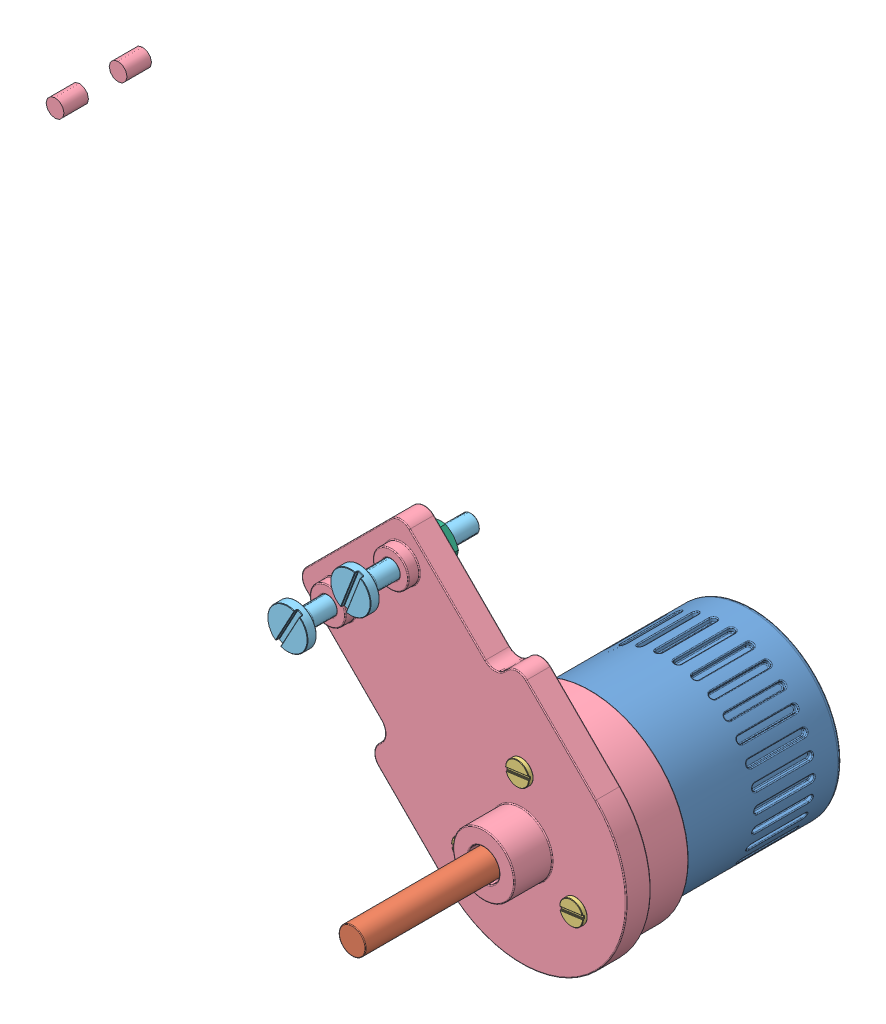
SolidWorks assembly Motor Assembly - other one, configuration Default. Lengths in mm.
Overall size (36.41 36.41 45.5).
13 component instances, 7 part files, 7 mates.
Components (placement in the parent):
- Motor-1: Motor [Default] at (-25.3397 14.6852 35.1852) size (20 20 26)
- Motor Shaft-1: Motor Shaft [Default] at (-25.3397 14.6852 55.1852) x (0.582298 0.812976 0) z (0 0 1) size (3 3 25)
- 1.25mm screw-1: 1.25mm screw [Default] at (-25.3397 21.6852 36.1852) x (0.133353 -0.991069 0) z (0 0 -1) size (2.65 2.65 7.5)
- 1.25mm screw-2: 1.25mm screw [Default] at (-31.4018 11.1852 36.1852) x (0.133353 -0.991069 0) z (0 0 -1) size (2.65 2.65 7.5)
- 1.25mm screw-3: 1.25mm screw [Default] at (-19.2775 11.1852 36.1852) x (0.133353 -0.991069 0) z (0 0 -1) size (2.65 2.65 7.5)
- Part6^Motor Assembly - other one-1: Part6^Motor Assembly - other one [Default] at origin (virtual)
- Moter Mounting Bracket-1: Moter Mounting Bracket [Default] at (-125.3397 14.6852 33.4352) size (65.08 65.08 12)
- 2mm screw and nut-7: 2mm screw and nut [Default] at (-38.7747 35.1913 40.9352) x (0.932837 -0.360298 0) z (0 0 -1) size (4.5 4.62 13.5)
  - 2mm screw-1: 2mm screw [Default] at origin size (4.5 4.5 13.5)
  - 2mm nut-1: 2mm nut [Default] at (0 0 7.5) size (4 4.62 1.5)
- 2mm screw and nut-8: 2mm screw and nut [Default] at (-45.8458 28.1202 40.9352) x (0.879702 -0.475526 0) z (0 0 -1) size (4.5 4.62 13.5)
  - 2mm screw-1: 2mm screw [Default] at origin size (4.5 4.5 13.5)
  - 2mm nut-1: 2mm nut [Default] at (0 0 7.5) size (4 4.62 1.5)
Mates (geometry in assembly coordinates):
- Coincident2: coincident anti-aligned: plane of Motor-1 through (-25.3397 14.6852 30.1852) normal (0 0 1); plane of Motor Shaft-1 through (-25.3397 14.6852 30.1852) normal (0 0 -1)
- Coincident3: coincident anti-aligned: plane of Motor-1 through (-25.3397 14.6852 35.1852) normal (0 0 1); plane of Moter Mounting Bracket-1 through (-25.3397 14.6852 35.1852) normal (0 0 -1)
- Concentric1: concentric aligned: cylinder of Motor Shaft-1 through (-25.3397 14.6852 30.1852) axis (0 0 1) radius 1.5; cylinder of Moter Mounting Bracket-1 through (-25.3397 14.6852 30.2355) axis (0 0 1) radius 1.75
- Coincident4: coincident anti-aligned: plane of Moter Mounting Bracket-1 through (-25.3397 14.6852 33.4352) normal (0 0 -1); plane of 2mm screw and nut-7/2mm nut-1 through (-38.7747 35.1913 33.4352) normal (0 0 1)
- Concentric2: concentric anti-aligned: cylinder of Moter Mounting Bracket-1 through (-38.7747 35.1913 37.4352) axis (0 0 -1) radius 1; cylinder of 2mm screw and nut-7/2mm screw-1 through (-38.7747 35.1913 28.4352) axis (0 0 1) radius 1
- Coincident5: coincident anti-aligned: plane of Moter Mounting Bracket-1 through (-25.3397 14.6852 33.4352) normal (0 0 -1); plane of 2mm screw and nut-8/2mm nut-1 through (-45.8458 28.1202 33.4352) normal (0 0 1)
- Concentric3: concentric anti-aligned: cylinder of Moter Mounting Bracket-1 through (-45.8458 28.1202 37.4352) axis (0 0 -1) radius 1; cylinder of 2mm screw and nut-8/2mm screw-1 through (-45.8458 28.1202 28.4352) axis (0 0 1) radius 1
